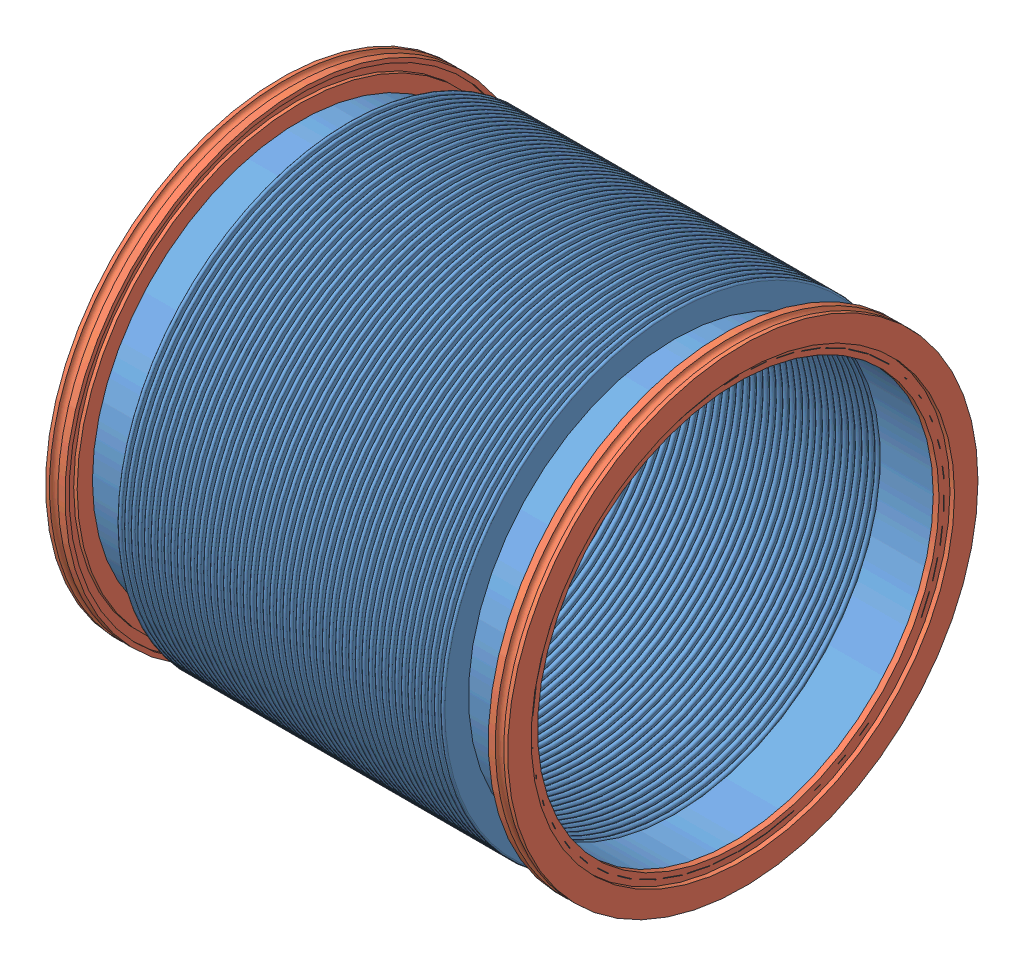
SolidWorks assembly 822004, configuration Default. Lengths in mm.
Overall size (284.99 290.07 290.07).
3 component instances, 2 part files, 6 mates.
Components (placement in the parent):
- 040611-1: 040611 [Default] at (-52.091 147.1721 230.7154) size (279.4 285.75 285.75)
- 813004-1: 813004 [Default] at (-54.885 147.1721 230.7154) x (1 0 0) z (0 0 -1) size (11.94 290.07 290.07)
- 813004-5: 813004 [Default] at (230.103 147.1721 230.7154) x (-1 0 0) z (0 0 -1) size (11.94 290.07 290.07)
Mates (geometry in assembly coordinates):
- Concentric1: concentric: cylinder of 040611-1 through (-52.091 147.1721 230.7154) axis (-1 0 0) radius 127.3048; cylinder of 813004-1 through (-54.885 147.1721 230.7154) axis (-1 0 0) radius 123.825
- Coincident1: coincident: plane of 040611-1 through (-52.091 147.1721 230.7154) normal (-1 0 0); plane of 813004-1 through (-52.091 114.5125 111.2751) normal (-1 0 0)
- Concentric2: concentric: cylinder of 040611-1 through (-52.091 147.1721 230.7154) axis (-1 0 0) radius 127.3048; cylinder of 813004-5 through (230.103 147.1721 230.7154) axis (1 0 0) radius 145.034
- Coincident2: coincident: plane of 040611-1 through (227.309 274.4769 230.7154) normal (1 0 0); plane of 813004-5 through (227.309 248.4813 301.9129) normal (1 0 0)
- Coincident3: coincident anti-aligned: plane of 040611-1 through (-52.091 147.1721 230.7154) normal (0 0 1); plane of 813004-1
- Coincident4: coincident aligned: plane of 813004-1 through (-54.885 147.1721 230.7154) normal (0 0 -1); plane of 813004-5
